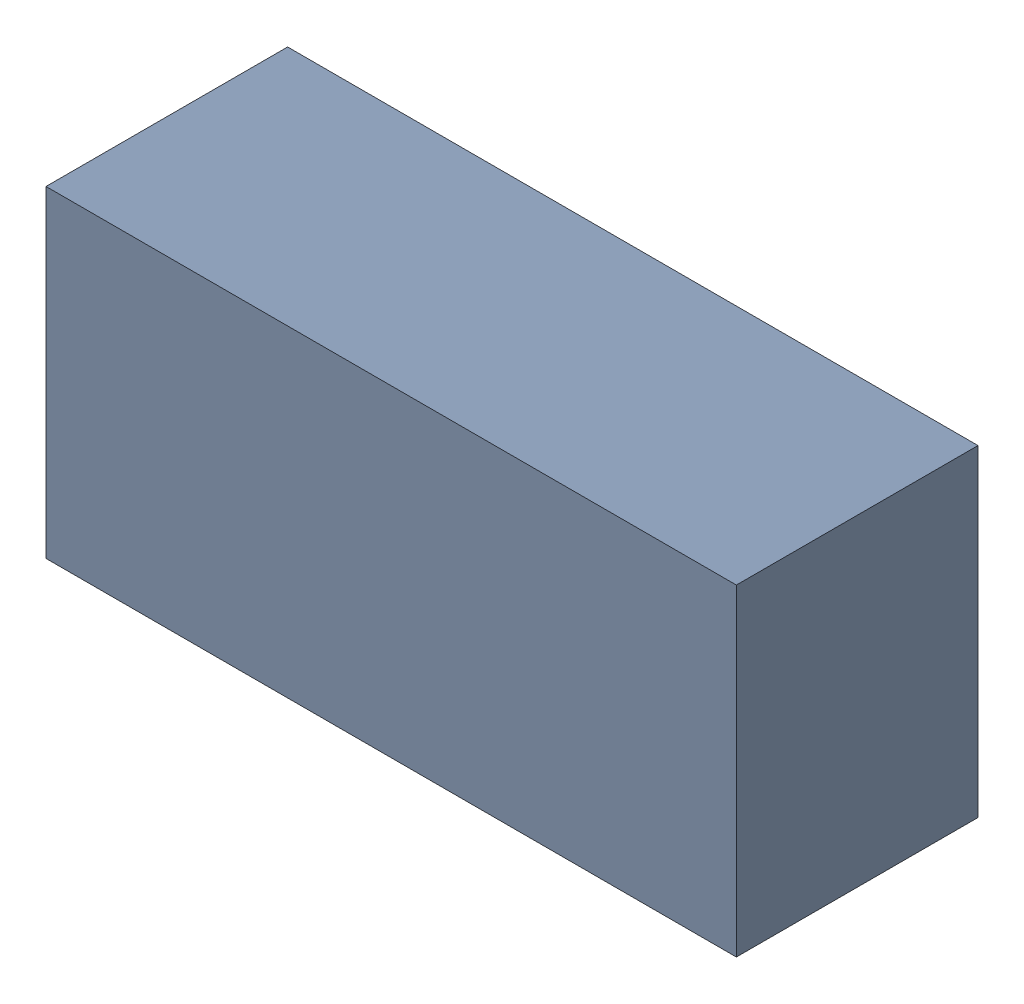
SolidWorks assembly U4Kanaloa_v2.0.0_Power, configuration Default. Lengths in mm.
Overall size (3 1.4 1.05).
2 component instances, 1 part files, 0 mates.
Components (placement in the parent):
- 378153792-1: 378153792 [Default] at (118.4402 35.6362 -2.2024) size (3 1.4 1.05)
  - Extruded_23-1: Extruded_23 [Default] at origin size (3 1.4 1.05)
